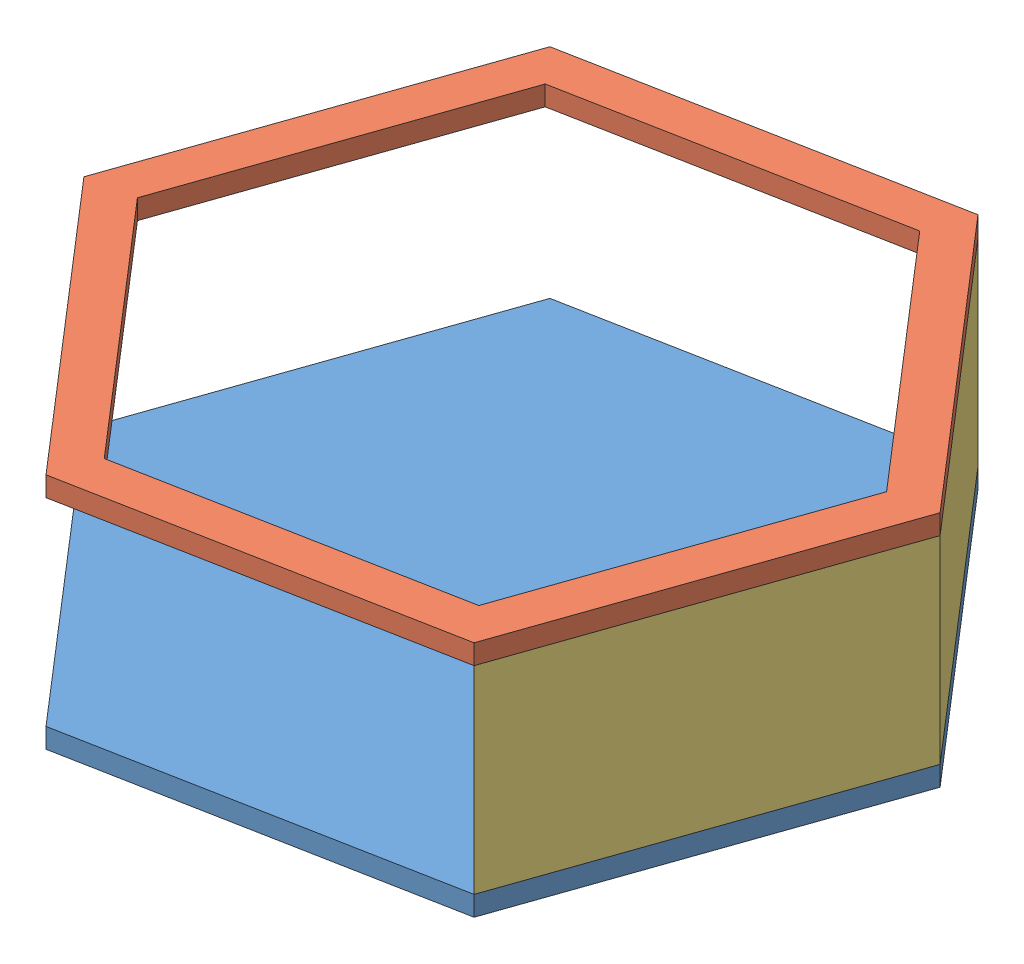
SolidWorks assembly Hivendfinal, configuration Default. Lengths in mm.
Overall size (423.31 120 348.94).
4 component instances, 3 part files, 5 mates.
Components (placement in the parent):
- hivendframebase-1: hivendframebase [Default] at (116.3758 184.4889 292.0274) size (362.96 10 348.94)
- hivendframedoor-2: hivendframedoor [Default] at (116.3758 294.4889 292.0274) size (362.96 10 348.94)
- Side-1: Side [Default] at (116.3758 194.4889 292.0274) size (124.51 100 142.02)
- Side-2: Side [Default] at (116.3758 194.4889 292.0274) x (0.5 0 0.866025) z (-0.866025 0 0.5) size (124.51 100 142.02)
Mates (geometry in assembly coordinates):
- Coincident6: coincident anti-aligned: plane of hivendframebase-1 through (116.3758 194.4889 292.0274) normal (0 1 0); plane of Side-1 through (116.3758 194.4889 292.0274) normal (0 -1 0)
- Coincident7: coincident: point of hivendframebase-1; point of Side-1
- Coincident10: coincident: point of hivendframedoor-2; point of Side-1
- Coincident11: coincident: point of hivendframebase-1; point of Side-2
- Coincident12: coincident aligned: line of hivendframebase-1 through (237.0902 194.4889 431.8866) axis (0.328901 0 -0.944364); line of Side-2 through (237.0902 194.4889 431.8866) axis (0.328901 0 -0.944364)
